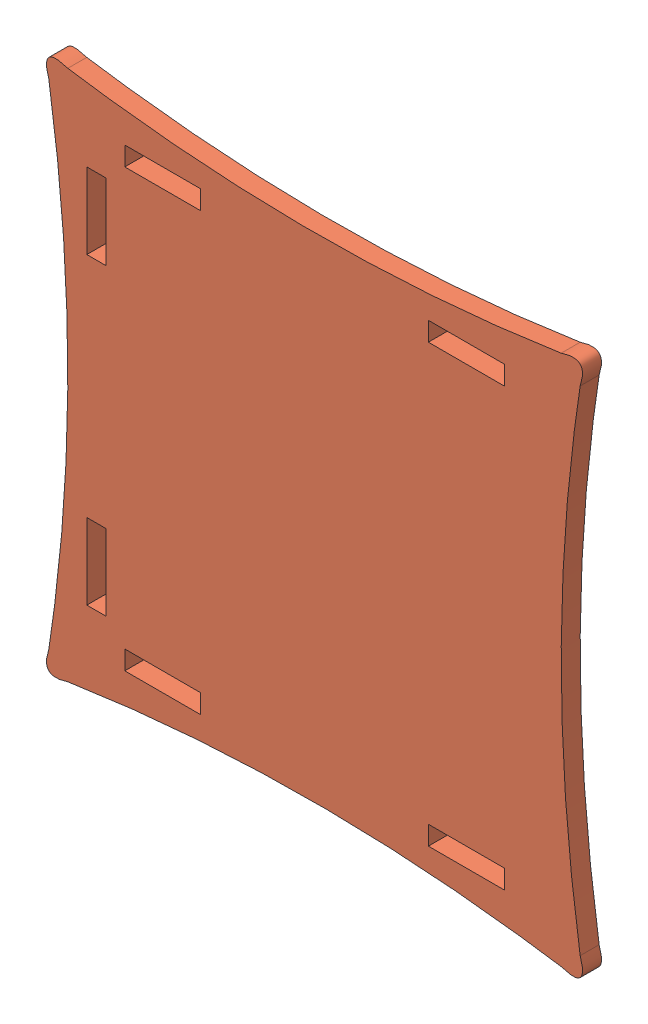
SolidWorks assembly Assem1, configuration Default. Lengths in mm.
Overall size (180.97 180.97 12.7).
2 component instances, 2 part files, 2 mates.
Components (placement in the parent):
- Drawer Base-1: Drawer Base [Default] at (-110.393 -85.0002 28.5118) size (139.7 139.7 6.35)
- Bottom-1: Bottom [Default] at (-129.443 73.7498 34.8618) x (0 -1 0) z (0 0 1) size (180.97 180.97 6.35)
Mates (geometry in assembly coordinates):
- Coincident2: coincident: line of Drawer Base-1 through (-110.393 -85.0002 34.8618) axis (1 0 0); line of Bottom-1 through (-78.9743 -85.0002 34.8618) axis (-1 0 0)
- Coincident3: coincident anti-aligned: line of Drawer Base-1 through (-110.393 54.6998 34.8618) axis (0 -1 0); line of Bottom-1 through (-110.393 22.9498 34.8618) axis (0 1 0)
